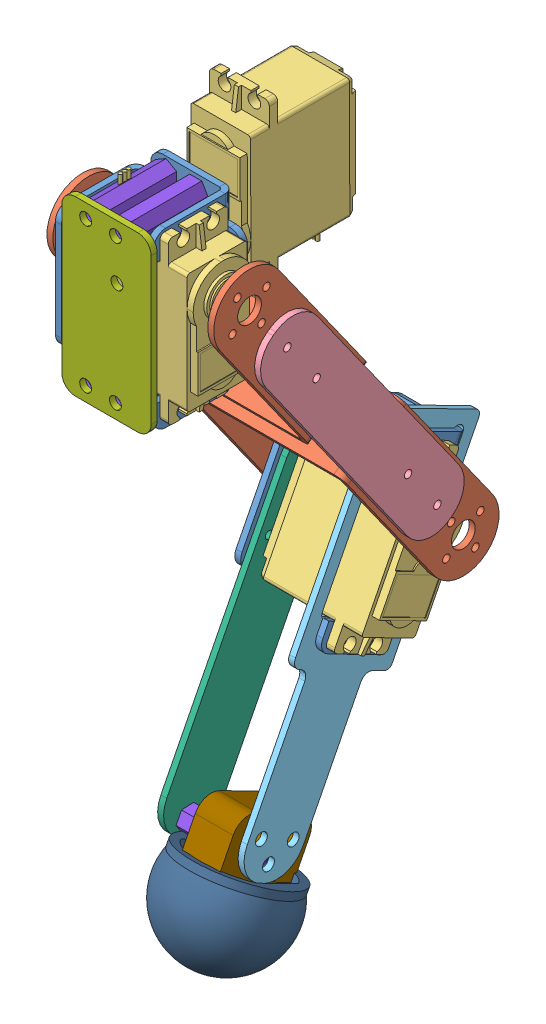
SolidWorks assembly leg, configuration Default. Lengths in mm.
Overall size (60 259.98 116.66).
19 component instances, 10 part files, 51 mates.
Components (placement in the parent):
- Multi Purpose Bracket-1: Multi Purpose Bracket [Défaut] at (0.2403 42.0249 -104.6986) x (0 0.890806 -0.454383) z (1 0 0) size (58 27 37.5)
- U Long Bracket-2: U Long Bracket [Défaut] at (25.2403 101.7982 -65.7711) x (-1 0 0) z (0 -0.578856 0.81543) size (56 65 24)
- Parça2 - Kopya-1: Parça2 - Kopya [Varsayılan] at (41.8386 78.3933 -95.2747) x (0 0.890806 -0.454383) z (0 -0.454383 -0.890806) size (56.95 39.84 20.1)
- leg_upper_1-1: leg_upper_1 [Default] at (-2.7597 109.137 -60.5614) x (0 0.81543 0.578856) z (0 -0.578856 0.81543) size (102 2 21.12)
- leg_upper_1-2: leg_upper_1 [Default] at (55.2403 109.137 -60.5614) x (0 -0.81543 -0.578856) z (0 0.578856 -0.81543) size (102 2 21.12)
- leg_lower_1-1: leg_lower_1 [Default] at (29.2403 3.3504 -68.2787) x (0 0.890806 -0.454383) z (0 -0.454383 -0.890806) size (123.5 2 37)
- leg_lower_2-1: leg_lower_2 [Default] at (2.2403 3.3504 -68.2787) x (0 0.890806 -0.454383) z (0 -0.454383 -0.890806) size (108.5 2 21.12)
- U Long Bracket-3: U Long Bracket [Défaut] at (25.2403 116.4759 -55.3517) x (1 0 0) z (0 -0.578856 0.81543) size (56 65 24)
- Multi Purpose Bracket-2: Multi Purpose Bracket [Défaut] at (0.2403 148.6937 -39.5423) x (0 1 0) z (1 0 0) size (58 27 37.5)
- Parça2 - Kopya-2: Parça2 - Kopya [Varsayılan] at (41.8386 178.1786 -14.6224) x (0 1 0) z (0 0 -1) size (56.95 39.84 20.1)
- hip_1-1: hip_1 [Default] at (19.3703 148.6937 -12.5423) size (30 58 2)
- hex spacer standoff nut M4 L25.stp-1: hex spacer standoff nut M4 L25.stp [Default] at (22.3703 172.9437 -37.5423) x (0.869844 -0.493326 0) z (0 0 1) size (7 8.08 25)
- hex spacer standoff nut M4 L25.stp-2: hex spacer standoff nut M4 L25.stp [Default] at (22.3703 124.4437 -37.5423) size (7 8.08 25)
- hex spacer standoff nut M4 L25.stp-3: hex spacer standoff nut M4 L25.stp [Default] at (12.3703 124.4437 -37.5423) size (7 8.08 25)
- hex spacer standoff nut M4 L25.stp-4: hex spacer standoff nut M4 L25.stp [Default] at (12.3703 172.9437 -37.5423) size (7 8.08 25)
- Parça2 - Kopya-3: Parça2 - Kopya [Varsayılan] at (32.9621 140.9816 -45.944) x (0.002264 -0.999997 0) z (-0.999997 -0.002264 0) size (56.95 39.84 20.1)
- foot-1: foot [Default] at (22.8703 -37.6267 -47.3771) x (0 0.454383 0.890806) z (-1 0 0) size (32 41 32)
- hex spacer standoff nut M4 L25.stp-5: hex spacer standoff nut M4 L25.stp [Default] at (4.2403 -26.4916 -53.0569) x (0 -0.998653 -0.051896) z (1 0 0) size (7 8.08 25)
- foot_grip-1: foot_grip [Default] at (22.8703 -37.6267 -47.3771) x (1 0 0) z (0 0.454383 0.890806) size (38 28.5 38)
Mates (geometry in assembly coordinates):
- Concentric1: concentric aligned: cylinder of Multi Purpose Bracket-1 through (33.2403 72.6555 -98.017) axis (1 0 0) radius 2; cylinder of Parça2 - Kopya-1 through (-5.1597 72.6555 -98.017) axis (1 0 0) radius 2.13
- Coincident1: coincident anti-aligned: plane of Multi Purpose Bracket-1 through (33.2403 42.0249 -104.6986) normal (1 0 0); plane of Parça2 - Kopya-1 through (33.2403 61.7246 -109.3362) normal (-1 0 0)
- Parallel1: parallel anti-aligned: plane of Multi Purpose Bracket-1 through (0.2403 42.0249 -104.6986) normal (0 0.454383 0.890806); plane of Parça2 - Kopya-1 through (41.8386 78.3933 -95.2747) normal (0 -0.454383 -0.890806)
- Concentric2: concentric anti-aligned: cylinder of Multi Purpose Bracket-1 through (2.2403 58.5804 -96.4505) axis (1 0 0) radius 1.5; cylinder of U Long Bracket-2 through (-2.7597 58.5804 -96.4505) axis (-1 0 0) radius 4
- Distance1: distance = 1 mm aligned: plane of U Long Bracket-2 through (-0.7597 94.8519 -55.986) normal (1 0 0); plane of Multi Purpose Bracket-1 through (0.2403 42.0249 -104.6986) normal (1 0 0)
- Concentric3: concentric aligned: cylinder of U Long Bracket-2 through (-2.7597 58.5804 -96.4505) axis (-1 0 0) radius 4; circle of leg_upper_1-1
- Coincident4: coincident anti-aligned: plane of U Long Bracket-2 through (-2.7597 94.8519 -55.986) normal (-1 0 0); plane of leg_upper_1-1 through (-2.7597 109.137 -60.5614) normal (1 0 0)
- Parallel2: parallel aligned: plane of U Long Bracket-2 through (0.2403 92.4056 -57.7225) normal (0 -0.578856 0.81543); plane of leg_upper_1-1 through (-4.7597 61.4384 -81.4735) normal (0 -0.578856 0.81543)
- Concentric4: concentric aligned: cylinder of Multi Purpose Bracket-1 through (2.2403 58.5804 -96.4505) axis (1 0 0) radius 1.5; circle of leg_lower_1-1
- Parallel3: parallel aligned: plane of Multi Purpose Bracket-1 through (0.2403 60.2864 -114.0134) normal (0 -0.454383 -0.890806); plane of leg_lower_1-1 through (31.2403 -1.4471 -77.6842) normal (0 -0.454383 -0.890806)
- Concentric5: concentric anti-aligned: cylinder of U Long Bracket-2 through (-2.7597 58.5804 -96.4505) axis (-1 0 0) radius 4; cylinder of leg_lower_1-2 through (10 14.87 2.3492) axis (0 0 1) radius 5
- Parallel4: parallel aligned: plane of Multi Purpose Bracket-1 through (2.2403 72.5547 -89.9616) normal (0 0.454383 0.890806); plane of leg_lower_1-2 through (-52 25.4284 2.3492) normal (0 1 0)
- Concentric6: concentric anti-aligned: cylinder of Multi Purpose Bracket-1 through (2.2403 58.5804 -96.4505) axis (1 0 0) radius 1.5; cylinder of leg_lower_2-1 through (4.2403 58.5804 -96.4505) axis (-1 0 0) radius 5
- Parallel5: parallel aligned: plane of Multi Purpose Bracket-1 through (2.2403 72.5547 -89.9616) normal (0 0.454383 0.890806); plane of leg_lower_2-1 through (4.2403 8.148 -58.8733) normal (0 0.454383 0.890806)
- Concentric7: concentric anti-aligned: cylinder of U Long Bracket-3 through (53.2403 159.6937 -24.6723) axis (1 0 0) radius 4; circle of leg_upper_1-1
- Coincident9: coincident anti-aligned: plane of leg_upper_1-1 through (-2.7597 109.137 -60.5614) normal (1 0 0); plane of U Long Bracket-3 through (-2.7597 162.5326 -7.9409) normal (-1 0 0)
- Parallel6: parallel aligned: plane of leg_upper_1-1 through (-4.7597 61.4384 -81.4735) normal (0 -0.578856 0.81543); plane of U Long Bracket-3 through (0.2403 111.1605 -44.4088) normal (0 -0.578856 0.81543)
- Concentric8: concentric aligned: cylinder of U Long Bracket-3 through (53.2403 159.6937 -24.6723) axis (1 0 0) radius 4; cylinder of Multi Purpose Bracket-2 through (2.2403 159.6937 -24.6723) axis (1 0 0) radius 1.5
- Distance2: distance = 1 mm aligned: plane of Multi Purpose Bracket-2 through (0.2403 148.6937 -39.5423) normal (1 0 0); plane of U Long Bracket-3 through (-0.7597 162.5326 -7.9409) normal (1 0 0)
- Concentric9: concentric aligned: cylinder of Multi Purpose Bracket-2 through (2.2403 159.6937 -24.6723) axis (1 0 0) radius 1.5; cylinder of Parça2 - Kopya-2 through (35.9803 159.6937 -24.6723) axis (1 0 0) radius 3
- Coincident12: coincident anti-aligned: plane of Multi Purpose Bracket-2 through (33.2403 148.6937 -39.5423) normal (1 0 0); plane of Parça2 - Kopya-2 through (33.2403 169.7193 -34.7224) normal (-1 0 0)
- Parallel7: parallel anti-aligned: plane of Multi Purpose Bracket-2 through (0.2403 169.1937 -37.5423) normal (0 0 1); plane of Parça2 - Kopya-2 through (41.8386 178.1786 -34.7224) normal (0 0 -1)
- Parallel9: parallel: plane of Multi Purpose Bracket-2 through (0.2403 148.6937 -39.5423) normal (0 0 1)
- Parallel10: parallel aligned: plane of Multi Purpose Bracket-2 through (0.0451 132.5098 -23.858) normal (0 1 0)
- Distance3: distance = 25 mm anti-aligned: plane of hip_1-1 through (19.3703 148.6937 -12.5423) normal (0 0 -1); plane of Multi Purpose Bracket-2 through (0.2403 169.1937 -37.5423) normal (0 0 1)
- Concentric10: concentric: cylinder of Multi Purpose Bracket-2 through (19.3703 148.6937 -37.5423) axis (0 0 1) radius 1.5; point of hip_1-1
- Coincident18: coincident anti-aligned: plane of Multi Purpose Bracket-1 through (31.2403 42.0249 -104.6986) normal (-1 0 0); plane of leg_lower_1-1 through (31.2403 3.3504 -68.2787) normal (1 0 0)
- Coincident19: coincident anti-aligned: plane of Multi Purpose Bracket-1 through (2.2403 72.5547 -89.9616) normal (1 0 0); plane of leg_lower_2-1 through (2.2403 3.3504 -68.2787) normal (-1 0 0)
- Concentric11: concentric aligned: cylinder of Multi Purpose Bracket-2 through (22.3703 172.9437 -37.5423) axis (0 0 1) radius 2; circle of hex spacer standoff nut M4 L25.stp-1
- Coincident20: coincident anti-aligned: plane of Multi Purpose Bracket-2 through (0.2403 169.1937 -37.5423) normal (0 0 1); plane of hex spacer standoff nut M4 L25.stp-1 through (22.3703 172.9437 -37.5423) normal (0 0 -1)
- Concentric12: concentric aligned: cylinder of Multi Purpose Bracket-2 through (12.3703 172.9437 -37.5423) axis (0 0 1) radius 2; circle of hex spacer standoff nut M4 L25.stp-4
- Coincident21: coincident anti-aligned: plane of Multi Purpose Bracket-2 through (0.2403 169.1937 -37.5423) normal (0 0 1); plane of hex spacer standoff nut M4 L25.stp-4 through (12.3703 172.9437 -37.5423) normal (0 0 -1)
- Coincident22: coincident anti-aligned: plane of Multi Purpose Bracket-2 through (0.2403 169.1937 -37.5423) normal (0 0 1); plane of hex spacer standoff nut M4 L25.stp-2 through (22.3703 124.4437 -37.5423) normal (0 0 -1)
- Concentric13: concentric aligned: cylinder of Multi Purpose Bracket-2 through (22.3703 124.4437 -37.5423) axis (0 0 1) radius 2; circle of hex spacer standoff nut M4 L25.stp-2
- Concentric14: concentric aligned: cylinder of Multi Purpose Bracket-2 through (12.3703 124.4437 -37.5423) axis (0 0 1) radius 2; circle of hex spacer standoff nut M4 L25.stp-3
- Coincident23: coincident anti-aligned: plane of Multi Purpose Bracket-2 through (0.2403 169.1937 -37.5423) normal (0 0 1); plane of hex spacer standoff nut M4 L25.stp-3 through (12.3703 124.4437 -37.5423) normal (0 0 -1)
- Concentric15: concentric aligned: cylinder of U Long Bracket-2 through (-2.7597 58.5804 -96.4505) axis (-1 0 0) radius 4; circle of leg_upper_1-2
- Concentric16: concentric anti-aligned: cylinder of U Long Bracket-3 through (53.2403 159.6937 -24.6723) axis (1 0 0) radius 4; circle of leg_upper_1-2
- Coincident24: coincident anti-aligned: plane of U Long Bracket-2 through (53.2403 41.849 -93.6116) normal (1 0 0); plane of leg_upper_1-2 through (53.2403 109.137 -60.5614) normal (-1 0 0)
- Concentric17: concentric aligned: cylinder of Multi Purpose Bracket-2 through (22.8703 159.4437 -37.5423) axis (0 0 1) radius 4; cylinder of Parça2 - Kopya-3 through (22.8703 159.4437 -51.8023) axis (0 0 1) radius 3
- Distance4: distance = 15 mm aligned: plane of Parça2 - Kopya-3 through (12.7517 189.6953 -54.5423) normal (0 0 -1); plane of Multi Purpose Bracket-2 through (0.2403 169.1937 -39.5423) normal (0 0 -1)
- Distance5: distance = 2 mm anti-aligned: plane of leg_lower_1-1 through (29.2403 3.3504 -68.2787) normal (-1 0 0); plane of foot-1 through (29.2403 -37.6267 -47.3771) normal (1 0 0)
- Coincident27: coincident anti-aligned: plane of leg_lower_1-1 through (29.2403 3.3504 -68.2787) normal (0 -0.454383 -0.890806); plane of foot-1 through (22.8703 -37.6267 -47.3771) normal (0 0.454383 0.890806)
- Coincident28: coincident anti-aligned: plane of foot-1 through (22.8703 -37.6267 -47.3771) normal (-1 0 0)
- Concentric18: concentric aligned: cylinder of leg_lower_1-1 through (31.2403 -26.4916 -53.0569) axis (-1 0 0) radius 2; circle of hex spacer standoff nut M4 L25.stp-5
- Coincident29: coincident anti-aligned: plane of leg_lower_1-1 through (29.2403 3.3504 -68.2787) normal (-1 0 0); plane of hex spacer standoff nut M4 L25.stp-5 through (29.2403 -26.4916 -53.0569) normal (1 0 0)
- Parallel13: parallel aligned: plane of foot-1 through (38.8703 -29.9304 -55.2879) normal (0 0.998653 0.051896); plane of hex spacer standoff nut M4 L25.stp-5 through (4.2403 -22.8914 -54.8933) normal (0 0.998653 0.051896)
- Tangent2: tangent: sphere of foot-1
- Concentric19: concentric: sphere of foot-1; sphere of foot_grip-1
- Parallel14: parallel aligned: plane of foot-1 through (38.8713 -31.391 -50.5578) normal (0 0.890806 -0.454383); plane of foot_grip-1 through (22.8703 -29.164 -51.6937) normal (0 0.890806 -0.454383)
- Parallel15: parallel anti-aligned: plane of foot-1 through (16.5003 -37.6267 -47.3771) normal (-1 0 0); plane of foot_grip-1 through (10.0835 -29.164 -51.6937) normal (1 0 0)
